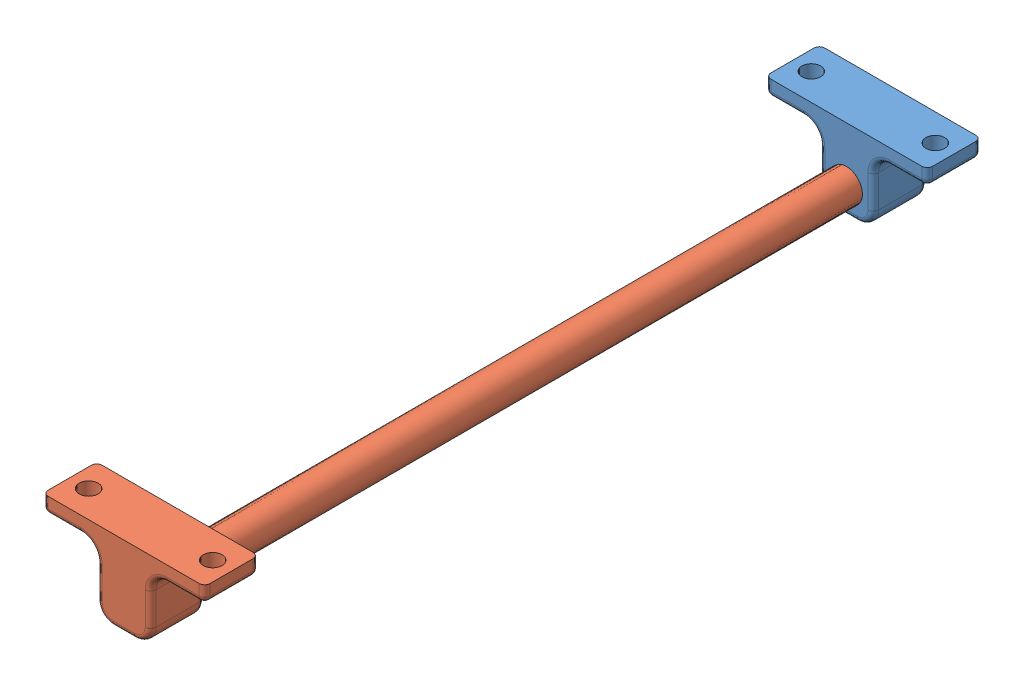
SolidWorks assembly rinia_rail, configuration ﾃﾞﾌｫﾙﾄ. Lengths in mm.
Overall size (30 15 144).
2 component instances, 2 part files, 3 mates.
Components (placement in the parent):
- shaftholder-1: shaftholder [ﾃﾞﾌｫﾙﾄ] at (-9.9946 -2.4519 30) size (30 15 10)
- shaft_6_4-1: shaft_6_4 [ﾃﾞﾌｫﾙﾄ] at (-9.9946 -2.4519 40) size (30 15 139)
Mates (geometry in assembly coordinates):
- 同心円1: concentric aligned: circle of shaftholder-1; circle of shaft_6_4-1
- 一致1: coincident anti-aligned: plane of shaftholder-1 through (-9.9946 -2.4519 40) normal (0 0 1); plane of shaft_6_4-1 through (-9.9946 -2.4519 40) normal (0 0 -1)
- 一致2: coincident aligned: plane of shaftholder-1 through (-9.9946 7.5481 40) normal (0 1 0); plane of shaft_6_4-1 through (-9.9946 7.5481 174) normal (0 1 0)
